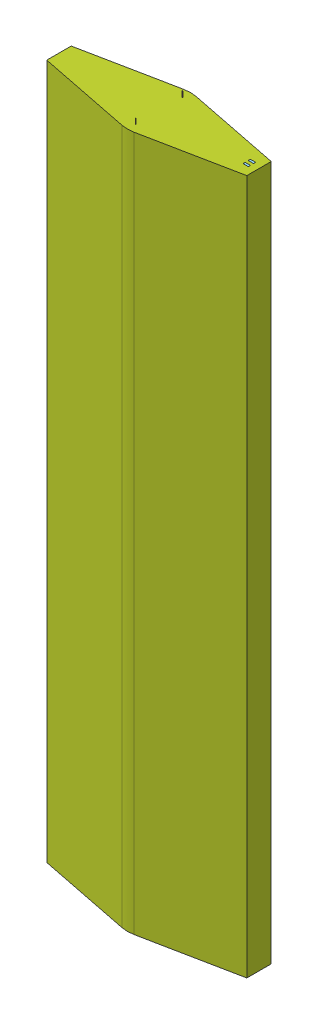
SolidWorks assembly RealString, configuration 默认. Lengths in mm.
Overall size (380 1330.46 350.65).
241 component instances, 7 part files, 3 mates.
Components (placement in the parent):
- RealUnit-1: RealUnit [默认] at origin size (374.87 90.61 350.65)
  - BEGeDet-1: BEGeDet [默认] at (2.9686 -23.0613 80) size (80 40 80)
  - InnerShell-IV-1: InnerShell-IV [默认] at (2.9686 -23.1113 80) x (0.656103 0 0.754671) z (-0.754671 0 0.656103) size (89 50 89)
  - RealOuterShell-IV-Part-3: RealOuterShell-IV-Part [默认] at (2.9686 -24.1113 80) x (-1 0 0) z (0 0 -1) size (357.21 73.56 262.25)
  - RealOuterShell-IV-Part-4: RealOuterShell-IV-Part [默认] at (2.5967 -24.1114 80) x (1 0.000332 0) z (0 0 1) size (357.21 73.56 262.25)
  - Electronics-1: Electronics [默认] at (2.9686 -48.2113 80) x (-1 0 0) z (0 0 -1) size (21.21 85 89.7)
  - ConnectionUnit-1: ConnectionUnit [默认] at (157.8605 -24.8554 155) x (-1 -0.000332 0) z (0 0 -1) size (23 75 26.4)
    - ConnectionRod-IV-1: ConnectionRod-IV [默认] at (-16.742 6.238 75) size (23 75 14)
    - RealSiPMArray-1: RealSiPMArray [默认] at (-11.242 1.238 75) x (-1 0 0) z (0 0 -1) size (3.97 70 26.4)
  - ConnectionUnit-2: ConnectionUnit [默认] at (-152.295 -24.9069 5) size (23 75 26.4)
    - ConnectionRod-IV-1: ConnectionRod-IV [默认] at (-16.742 6.238 75) size (23 75 14)
    - RealSiPMArray-1: RealSiPMArray [默认] at (-11.242 1.238 75) x (-1 0 0) z (0 0 -1) size (3.97 70 26.4)
- RealUnit-2: RealUnit [默认] at (0 65 0) size (374.87 90.61 350.65)
  - BEGeDet-1: BEGeDet [默认] at (2.9686 -23.0613 80) size (80 40 80)
  - InnerShell-IV-1: InnerShell-IV [默认] at (2.9686 -23.1113 80) x (0.656103 0 0.754671) z (-0.754671 0 0.656103) size (89 50 89)
  - RealOuterShell-IV-Part-3: RealOuterShell-IV-Part [默认] at (2.9686 -24.1113 80) x (-1 0 0) z (0 0 -1) size (357.21 73.56 262.25)
  - RealOuterShell-IV-Part-4: RealOuterShell-IV-Part [默认] at (2.5967 -24.1114 80) x (1 0.000332 0) z (0 0 1) size (357.21 73.56 262.25)
  - Electronics-1: Electronics [默认] at (2.9686 -48.2113 80) x (-1 0 0) z (0 0 -1) size (21.21 85 89.7)
  - ConnectionUnit-1: ConnectionUnit [默认] at (157.8605 -24.8554 155) x (-1 -0.000332 0) z (0 0 -1) size (23 75 26.4)
    - ConnectionRod-IV-1: ConnectionRod-IV [默认] at (-16.742 6.238 75) size (23 75 14)
    - RealSiPMArray-1: RealSiPMArray [默认] at (-11.242 1.238 75) x (-1 0 0) z (0 0 -1) size (3.97 70 26.4)
  - ConnectionUnit-2: ConnectionUnit [默认] at (-152.295 -24.9069 5) size (23 75 26.4)
    - ConnectionRod-IV-1: ConnectionRod-IV [默认] at (-16.742 6.238 75) size (23 75 14)
    - RealSiPMArray-1: RealSiPMArray [默认] at (-11.242 1.238 75) x (-1 0 0) z (0 0 -1) size (3.97 70 26.4)
- RealUnit-3: RealUnit [默认] at (0 130 0) size (374.87 90.61 350.65)
  - BEGeDet-1: BEGeDet [默认] at (2.9686 -23.0613 80) size (80 40 80)
  - InnerShell-IV-1: InnerShell-IV [默认] at (2.9686 -23.1113 80) x (0.656103 0 0.754671) z (-0.754671 0 0.656103) size (89 50 89)
  - RealOuterShell-IV-Part-3: RealOuterShell-IV-Part [默认] at (2.9686 -24.1113 80) x (-1 0 0) z (0 0 -1) size (357.21 73.56 262.25)
  - RealOuterShell-IV-Part-4: RealOuterShell-IV-Part [默认] at (2.5967 -24.1114 80) x (1 0.000332 0) z (0 0 1) size (357.21 73.56 262.25)
  - Electronics-1: Electronics [默认] at (2.9686 -48.2113 80) x (-1 0 0) z (0 0 -1) size (21.21 85 89.7)
  - ConnectionUnit-1: ConnectionUnit [默认] at (157.8605 -24.8554 155) x (-1 -0.000332 0) z (0 0 -1) size (23 75 26.4)
    - ConnectionRod-IV-1: ConnectionRod-IV [默认] at (-16.742 6.238 75) size (23 75 14)
    - RealSiPMArray-1: RealSiPMArray [默认] at (-11.242 1.238 75) x (-1 0 0) z (0 0 -1) size (3.97 70 26.4)
  - ConnectionUnit-2: ConnectionUnit [默认] at (-152.295 -24.9069 5) size (23 75 26.4)
    - ConnectionRod-IV-1: ConnectionRod-IV [默认] at (-16.742 6.238 75) size (23 75 14)
    - RealSiPMArray-1: RealSiPMArray [默认] at (-11.242 1.238 75) x (-1 0 0) z (0 0 -1) size (3.97 70 26.4)
- RealUnit-4: RealUnit [默认] at (0 195 0) size (374.87 90.61 350.65)
  - BEGeDet-1: BEGeDet [默认] at (2.9686 -23.0613 80) size (80 40 80)
  - InnerShell-IV-1: InnerShell-IV [默认] at (2.9686 -23.1113 80) x (0.656103 0 0.754671) z (-0.754671 0 0.656103) size (89 50 89)
  - RealOuterShell-IV-Part-3: RealOuterShell-IV-Part [默认] at (2.9686 -24.1113 80) x (-1 0 0) z (0 0 -1) size (357.21 73.56 262.25)
  - RealOuterShell-IV-Part-4: RealOuterShell-IV-Part [默认] at (2.5967 -24.1114 80) x (1 0.000332 0) z (0 0 1) size (357.21 73.56 262.25)
  - Electronics-1: Electronics [默认] at (2.9686 -48.2113 80) x (-1 0 0) z (0 0 -1) size (21.21 85 89.7)
  - ConnectionUnit-1: ConnectionUnit [默认] at (157.8605 -24.8554 155) x (-1 -0.000332 0) z (0 0 -1) size (23 75 26.4)
    - ConnectionRod-IV-1: ConnectionRod-IV [默认] at (-16.742 6.238 75) size (23 75 14)
    - RealSiPMArray-1: RealSiPMArray [默认] at (-11.242 1.238 75) x (-1 0 0) z (0 0 -1) size (3.97 70 26.4)
  - ConnectionUnit-2: ConnectionUnit [默认] at (-152.295 -24.9069 5) size (23 75 26.4)
    - ConnectionRod-IV-1: ConnectionRod-IV [默认] at (-16.742 6.238 75) size (23 75 14)
    - RealSiPMArray-1: RealSiPMArray [默认] at (-11.242 1.238 75) x (-1 0 0) z (0 0 -1) size (3.97 70 26.4)
- RealUnit-5: RealUnit [默认] at (0 260 0) size (374.87 90.61 350.65)
  - BEGeDet-1: BEGeDet [默认] at (2.9686 -23.0613 80) size (80 40 80)
  - InnerShell-IV-1: InnerShell-IV [默认] at (2.9686 -23.1113 80) x (0.656103 0 0.754671) z (-0.754671 0 0.656103) size (89 50 89)
  - RealOuterShell-IV-Part-3: RealOuterShell-IV-Part [默认] at (2.9686 -24.1113 80) x (-1 0 0) z (0 0 -1) size (357.21 73.56 262.25)
  - RealOuterShell-IV-Part-4: RealOuterShell-IV-Part [默认] at (2.5967 -24.1114 80) x (1 0.000332 0) z (0 0 1) size (357.21 73.56 262.25)
  - Electronics-1: Electronics [默认] at (2.9686 -48.2113 80) x (-1 0 0) z (0 0 -1) size (21.21 85 89.7)
  - ConnectionUnit-1: ConnectionUnit [默认] at (157.8605 -24.8554 155) x (-1 -0.000332 0) z (0 0 -1) size (23 75 26.4)
    - ConnectionRod-IV-1: ConnectionRod-IV [默认] at (-16.742 6.238 75) size (23 75 14)
    - RealSiPMArray-1: RealSiPMArray [默认] at (-11.242 1.238 75) x (-1 0 0) z (0 0 -1) size (3.97 70 26.4)
  - ConnectionUnit-2: ConnectionUnit [默认] at (-152.295 -24.9069 5) size (23 75 26.4)
    - ConnectionRod-IV-1: ConnectionRod-IV [默认] at (-16.742 6.238 75) size (23 75 14)
    - RealSiPMArray-1: RealSiPMArray [默认] at (-11.242 1.238 75) x (-1 0 0) z (0 0 -1) size (3.97 70 26.4)
- RealUnit-6: RealUnit [默认] at (0 325 0) size (374.87 90.61 350.65)
  - BEGeDet-1: BEGeDet [默认] at (2.9686 -23.0613 80) size (80 40 80)
  - InnerShell-IV-1: InnerShell-IV [默认] at (2.9686 -23.1113 80) x (0.656103 0 0.754671) z (-0.754671 0 0.656103) size (89 50 89)
  - RealOuterShell-IV-Part-3: RealOuterShell-IV-Part [默认] at (2.9686 -24.1113 80) x (-1 0 0) z (0 0 -1) size (357.21 73.56 262.25)
  - RealOuterShell-IV-Part-4: RealOuterShell-IV-Part [默认] at (2.5967 -24.1114 80) x (1 0.000332 0) z (0 0 1) size (357.21 73.56 262.25)
  - Electronics-1: Electronics [默认] at (2.9686 -48.2113 80) x (-1 0 0) z (0 0 -1) size (21.21 85 89.7)
  - ConnectionUnit-1: ConnectionUnit [默认] at (157.8605 -24.8554 155) x (-1 -0.000332 0) z (0 0 -1) size (23 75 26.4)
    - ConnectionRod-IV-1: ConnectionRod-IV [默认] at (-16.742 6.238 75) size (23 75 14)
    - RealSiPMArray-1: RealSiPMArray [默认] at (-11.242 1.238 75) x (-1 0 0) z (0 0 -1) size (3.97 70 26.4)
  - ConnectionUnit-2: ConnectionUnit [默认] at (-152.295 -24.9069 5) size (23 75 26.4)
    - ConnectionRod-IV-1: ConnectionRod-IV [默认] at (-16.742 6.238 75) size (23 75 14)
    - RealSiPMArray-1: RealSiPMArray [默认] at (-11.242 1.238 75) x (-1 0 0) z (0 0 -1) size (3.97 70 26.4)
- RealUnit-7: RealUnit [默认] at (0 390 0) size (374.87 90.61 350.65)
  - BEGeDet-1: BEGeDet [默认] at (2.9686 -23.0613 80) size (80 40 80)
  - InnerShell-IV-1: InnerShell-IV [默认] at (2.9686 -23.1113 80) x (0.656103 0 0.754671) z (-0.754671 0 0.656103) size (89 50 89)
  - RealOuterShell-IV-Part-3: RealOuterShell-IV-Part [默认] at (2.9686 -24.1113 80) x (-1 0 0) z (0 0 -1) size (357.21 73.56 262.25)
  - RealOuterShell-IV-Part-4: RealOuterShell-IV-Part [默认] at (2.5967 -24.1114 80) x (1 0.000332 0) z (0 0 1) size (357.21 73.56 262.25)
  - Electronics-1: Electronics [默认] at (2.9686 -48.2113 80) x (-1 0 0) z (0 0 -1) size (21.21 85 89.7)
  - ConnectionUnit-1: ConnectionUnit [默认] at (157.8605 -24.8554 155) x (-1 -0.000332 0) z (0 0 -1) size (23 75 26.4)
    - ConnectionRod-IV-1: ConnectionRod-IV [默认] at (-16.742 6.238 75) size (23 75 14)
    - RealSiPMArray-1: RealSiPMArray [默认] at (-11.242 1.238 75) x (-1 0 0) z (0 0 -1) size (3.97 70 26.4)
  - ConnectionUnit-2: ConnectionUnit [默认] at (-152.295 -24.9069 5) size (23 75 26.4)
    - ConnectionRod-IV-1: ConnectionRod-IV [默认] at (-16.742 6.238 75) size (23 75 14)
    - RealSiPMArray-1: RealSiPMArray [默认] at (-11.242 1.238 75) x (-1 0 0) z (0 0 -1) size (3.97 70 26.4)
- RealUnit-8: RealUnit [默认] at (0 455 0) size (374.87 90.61 350.65)
  - BEGeDet-1: BEGeDet [默认] at (2.9686 -23.0613 80) size (80 40 80)
  - InnerShell-IV-1: InnerShell-IV [默认] at (2.9686 -23.1113 80) x (0.656103 0 0.754671) z (-0.754671 0 0.656103) size (89 50 89)
  - RealOuterShell-IV-Part-3: RealOuterShell-IV-Part [默认] at (2.9686 -24.1113 80) x (-1 0 0) z (0 0 -1) size (357.21 73.56 262.25)
  - RealOuterShell-IV-Part-4: RealOuterShell-IV-Part [默认] at (2.5967 -24.1114 80) x (1 0.000332 0) z (0 0 1) size (357.21 73.56 262.25)
  - Electronics-1: Electronics [默认] at (2.9686 -48.2113 80) x (-1 0 0) z (0 0 -1) size (21.21 85 89.7)
  - ConnectionUnit-1: ConnectionUnit [默认] at (157.8605 -24.8554 155) x (-1 -0.000332 0) z (0 0 -1) size (23 75 26.4)
    - ConnectionRod-IV-1: ConnectionRod-IV [默认] at (-16.742 6.238 75) size (23 75 14)
    - RealSiPMArray-1: RealSiPMArray [默认] at (-11.242 1.238 75) x (-1 0 0) z (0 0 -1) size (3.97 70 26.4)
  - ConnectionUnit-2: ConnectionUnit [默认] at (-152.295 -24.9069 5) size (23 75 26.4)
    - ConnectionRod-IV-1: ConnectionRod-IV [默认] at (-16.742 6.238 75) size (23 75 14)
    - RealSiPMArray-1: RealSiPMArray [默认] at (-11.242 1.238 75) x (-1 0 0) z (0 0 -1) size (3.97 70 26.4)
- RealUnit-9: RealUnit [默认] at (0 520 0) size (374.87 90.61 350.65)
  - BEGeDet-1: BEGeDet [默认] at (2.9686 -23.0613 80) size (80 40 80)
  - InnerShell-IV-1: InnerShell-IV [默认] at (2.9686 -23.1113 80) x (0.656103 0 0.754671) z (-0.754671 0 0.656103) size (89 50 89)
  - RealOuterShell-IV-Part-3: RealOuterShell-IV-Part [默认] at (2.9686 -24.1113 80) x (-1 0 0) z (0 0 -1) size (357.21 73.56 262.25)
  - RealOuterShell-IV-Part-4: RealOuterShell-IV-Part [默认] at (2.5967 -24.1114 80) x (1 0.000332 0) z (0 0 1) size (357.21 73.56 262.25)
  - Electronics-1: Electronics [默认] at (2.9686 -48.2113 80) x (-1 0 0) z (0 0 -1) size (21.21 85 89.7)
  - ConnectionUnit-1: ConnectionUnit [默认] at (157.8605 -24.8554 155) x (-1 -0.000332 0) z (0 0 -1) size (23 75 26.4)
    - ConnectionRod-IV-1: ConnectionRod-IV [默认] at (-16.742 6.238 75) size (23 75 14)
    - RealSiPMArray-1: RealSiPMArray [默认] at (-11.242 1.238 75) x (-1 0 0) z (0 0 -1) size (3.97 70 26.4)
  - ConnectionUnit-2: ConnectionUnit [默认] at (-152.295 -24.9069 5) size (23 75 26.4)
    - ConnectionRod-IV-1: ConnectionRod-IV [默认] at (-16.742 6.238 75) size (23 75 14)
    - RealSiPMArray-1: RealSiPMArray [默认] at (-11.242 1.238 75) x (-1 0 0) z (0 0 -1) size (3.97 70 26.4)
- RealUnit-10: RealUnit [默认] at (0 585 0) size (374.87 90.61 350.65)
  - BEGeDet-1: BEGeDet [默认] at (2.9686 -23.0613 80) size (80 40 80)
  - InnerShell-IV-1: InnerShell-IV [默认] at (2.9686 -23.1113 80) x (0.656103 0 0.754671) z (-0.754671 0 0.656103) size (89 50 89)
  - RealOuterShell-IV-Part-3: RealOuterShell-IV-Part [默认] at (2.9686 -24.1113 80) x (-1 0 0) z (0 0 -1) size (357.21 73.56 262.25)
  - RealOuterShell-IV-Part-4: RealOuterShell-IV-Part [默认] at (2.5967 -24.1114 80) x (1 0.000332 0) z (0 0 1) size (357.21 73.56 262.25)
  - Electronics-1: Electronics [默认] at (2.9686 -48.2113 80) x (-1 0 0) z (0 0 -1) size (21.21 85 89.7)
  - ConnectionUnit-1: ConnectionUnit [默认] at (157.8605 -24.8554 155) x (-1 -0.000332 0) z (0 0 -1) size (23 75 26.4)
    - ConnectionRod-IV-1: ConnectionRod-IV [默认] at (-16.742 6.238 75) size (23 75 14)
    - RealSiPMArray-1: RealSiPMArray [默认] at (-11.242 1.238 75) x (-1 0 0) z (0 0 -1) size (3.97 70 26.4)
  - ConnectionUnit-2: ConnectionUnit [默认] at (-152.295 -24.9069 5) size (23 75 26.4)
    - ConnectionRod-IV-1: ConnectionRod-IV [默认] at (-16.742 6.238 75) size (23 75 14)
    - RealSiPMArray-1: RealSiPMArray [默认] at (-11.242 1.238 75) x (-1 0 0) z (0 0 -1) size (3.97 70 26.4)
- RealUnit-11: RealUnit [默认] at (0 650 0) size (374.87 90.61 350.65)
  - BEGeDet-1: BEGeDet [默认] at (2.9686 -23.0613 80) size (80 40 80)
  - InnerShell-IV-1: InnerShell-IV [默认] at (2.9686 -23.1113 80) x (0.656103 0 0.754671) z (-0.754671 0 0.656103) size (89 50 89)
  - RealOuterShell-IV-Part-3: RealOuterShell-IV-Part [默认] at (2.9686 -24.1113 80) x (-1 0 0) z (0 0 -1) size (357.21 73.56 262.25)
  - RealOuterShell-IV-Part-4: RealOuterShell-IV-Part [默认] at (2.5967 -24.1114 80) x (1 0.000332 0) z (0 0 1) size (357.21 73.56 262.25)
  - Electronics-1: Electronics [默认] at (2.9686 -48.2113 80) x (-1 0 0) z (0 0 -1) size (21.21 85 89.7)
  - ConnectionUnit-1: ConnectionUnit [默认] at (157.8605 -24.8554 155) x (-1 -0.000332 0) z (0 0 -1) size (23 75 26.4)
    - ConnectionRod-IV-1: ConnectionRod-IV [默认] at (-16.742 6.238 75) size (23 75 14)
    - RealSiPMArray-1: RealSiPMArray [默认] at (-11.242 1.238 75) x (-1 0 0) z (0 0 -1) size (3.97 70 26.4)
  - ConnectionUnit-2: ConnectionUnit [默认] at (-152.295 -24.9069 5) size (23 75 26.4)
    - ConnectionRod-IV-1: ConnectionRod-IV [默认] at (-16.742 6.238 75) size (23 75 14)
    - RealSiPMArray-1: RealSiPMArray [默认] at (-11.242 1.238 75) x (-1 0 0) z (0 0 -1) size (3.97 70 26.4)
- RealUnit-12: RealUnit [默认] at (0 715 0) size (374.87 90.61 350.65)
  - BEGeDet-1: BEGeDet [默认] at (2.9686 -23.0613 80) size (80 40 80)
  - InnerShell-IV-1: InnerShell-IV [默认] at (2.9686 -23.1113 80) x (0.656103 0 0.754671) z (-0.754671 0 0.656103) size (89 50 89)
  - RealOuterShell-IV-Part-3: RealOuterShell-IV-Part [默认] at (2.9686 -24.1113 80) x (-1 0 0) z (0 0 -1) size (357.21 73.56 262.25)
  - RealOuterShell-IV-Part-4: RealOuterShell-IV-Part [默认] at (2.5967 -24.1114 80) x (1 0.000332 0) z (0 0 1) size (357.21 73.56 262.25)
  - Electronics-1: Electronics [默认] at (2.9686 -48.2113 80) x (-1 0 0) z (0 0 -1) size (21.21 85 89.7)
  - ConnectionUnit-1: ConnectionUnit [默认] at (157.8605 -24.8554 155) x (-1 -0.000332 0) z (0 0 -1) size (23 75 26.4)
    - ConnectionRod-IV-1: ConnectionRod-IV [默认] at (-16.742 6.238 75) size (23 75 14)
    - RealSiPMArray-1: RealSiPMArray [默认] at (-11.242 1.238 75) x (-1 0 0) z (0 0 -1) size (3.97 70 26.4)
  - ConnectionUnit-2: ConnectionUnit [默认] at (-152.295 -24.9069 5) size (23 75 26.4)
    - ConnectionRod-IV-1: ConnectionRod-IV [默认] at (-16.742 6.238 75) size (23 75 14)
    - RealSiPMArray-1: RealSiPMArray [默认] at (-11.242 1.238 75) x (-1 0 0) z (0 0 -1) size (3.97 70 26.4)
- RealUnit-13: RealUnit [默认] at (0 780 0) size (374.87 90.61 350.65)
  - BEGeDet-1: BEGeDet [默认] at (2.9686 -23.0613 80) size (80 40 80)
  - InnerShell-IV-1: InnerShell-IV [默认] at (2.9686 -23.1113 80) x (0.656103 0 0.754671) z (-0.754671 0 0.656103) size (89 50 89)
  - RealOuterShell-IV-Part-3: RealOuterShell-IV-Part [默认] at (2.9686 -24.1113 80) x (-1 0 0) z (0 0 -1) size (357.21 73.56 262.25)
  - RealOuterShell-IV-Part-4: RealOuterShell-IV-Part [默认] at (2.5967 -24.1114 80) x (1 0.000332 0) z (0 0 1) size (357.21 73.56 262.25)
  - Electronics-1: Electronics [默认] at (2.9686 -48.2113 80) x (-1 0 0) z (0 0 -1) size (21.21 85 89.7)
  - ConnectionUnit-1: ConnectionUnit [默认] at (157.8605 -24.8554 155) x (-1 -0.000332 0) z (0 0 -1) size (23 75 26.4)
    - ConnectionRod-IV-1: ConnectionRod-IV [默认] at (-16.742 6.238 75) size (23 75 14)
    - RealSiPMArray-1: RealSiPMArray [默认] at (-11.242 1.238 75) x (-1 0 0) z (0 0 -1) size (3.97 70 26.4)
  - ConnectionUnit-2: ConnectionUnit [默认] at (-152.295 -24.9069 5) size (23 75 26.4)
    - ConnectionRod-IV-1: ConnectionRod-IV [默认] at (-16.742 6.238 75) size (23 75 14)
    - RealSiPMArray-1: RealSiPMArray [默认] at (-11.242 1.238 75) x (-1 0 0) z (0 0 -1) size (3.97 70 26.4)
- RealUnit-14: RealUnit [默认] at (0 845 0) size (374.87 90.61 350.65)
  - BEGeDet-1: BEGeDet [默认] at (2.9686 -23.0613 80) size (80 40 80)
  - InnerShell-IV-1: InnerShell-IV [默认] at (2.9686 -23.1113 80) x (0.656103 0 0.754671) z (-0.754671 0 0.656103) size (89 50 89)
  - RealOuterShell-IV-Part-3: RealOuterShell-IV-Part [默认] at (2.9686 -24.1113 80) x (-1 0 0) z (0 0 -1) size (357.21 73.56 262.25)
  - RealOuterShell-IV-Part-4: RealOuterShell-IV-Part [默认] at (2.5967 -24.1114 80) x (1 0.000332 0) z (0 0 1) size (357.21 73.56 262.25)
  - Electronics-1: Electronics [默认] at (2.9686 -48.2113 80) x (-1 0 0) z (0 0 -1) size (21.21 85 89.7)
  - ConnectionUnit-1: ConnectionUnit [默认] at (157.8605 -24.8554 155) x (-1 -0.000332 0) z (0 0 -1) size (23 75 26.4)
    - ConnectionRod-IV-1: ConnectionRod-IV [默认] at (-16.742 6.238 75) size (23 75 14)
    - RealSiPMArray-1: RealSiPMArray [默认] at (-11.242 1.238 75) x (-1 0 0) z (0 0 -1) size (3.97 70 26.4)
  - ConnectionUnit-2: ConnectionUnit [默认] at (-152.295 -24.9069 5) size (23 75 26.4)
    - ConnectionRod-IV-1: ConnectionRod-IV [默认] at (-16.742 6.238 75) size (23 75 14)
    - RealSiPMArray-1: RealSiPMArray [默认] at (-11.242 1.238 75) x (-1 0 0) z (0 0 -1) size (3.97 70 26.4)
- RealUnit-15: RealUnit [默认] at (0 910 0) size (374.87 90.61 350.65)
  - BEGeDet-1: BEGeDet [默认] at (2.9686 -23.0613 80) size (80 40 80)
  - InnerShell-IV-1: InnerShell-IV [默认] at (2.9686 -23.1113 80) x (0.656103 0 0.754671) z (-0.754671 0 0.656103) size (89 50 89)
  - RealOuterShell-IV-Part-3: RealOuterShell-IV-Part [默认] at (2.9686 -24.1113 80) x (-1 0 0) z (0 0 -1) size (357.21 73.56 262.25)
  - RealOuterShell-IV-Part-4: RealOuterShell-IV-Part [默认] at (2.5967 -24.1114 80) x (1 0.000332 0) z (0 0 1) size (357.21 73.56 262.25)
  - Electronics-1: Electronics [默认] at (2.9686 -48.2113 80) x (-1 0 0) z (0 0 -1) size (21.21 85 89.7)
  - ConnectionUnit-1: ConnectionUnit [默认] at (157.8605 -24.8554 155) x (-1 -0.000332 0) z (0 0 -1) size (23 75 26.4)
    - ConnectionRod-IV-1: ConnectionRod-IV [默认] at (-16.742 6.238 75) size (23 75 14)
    - RealSiPMArray-1: RealSiPMArray [默认] at (-11.242 1.238 75) x (-1 0 0) z (0 0 -1) size (3.97 70 26.4)
  - ConnectionUnit-2: ConnectionUnit [默认] at (-152.295 -24.9069 5) size (23 75 26.4)
    - ConnectionRod-IV-1: ConnectionRod-IV [默认] at (-16.742 6.238 75) size (23 75 14)
    - RealSiPMArray-1: RealSiPMArray [默认] at (-11.242 1.238 75) x (-1 0 0) z (0 0 -1) size (3.97 70 26.4)
- RealUnit-16: RealUnit [默认] at (0 975 0) size (374.87 90.61 350.65)
  - BEGeDet-1: BEGeDet [默认] at (2.9686 -23.0613 80) size (80 40 80)
  - InnerShell-IV-1: InnerShell-IV [默认] at (2.9686 -23.1113 80) x (0.656103 0 0.754671) z (-0.754671 0 0.656103) size (89 50 89)
  - RealOuterShell-IV-Part-3: RealOuterShell-IV-Part [默认] at (2.9686 -24.1113 80) x (-1 0 0) z (0 0 -1) size (357.21 73.56 262.25)
  - RealOuterShell-IV-Part-4: RealOuterShell-IV-Part [默认] at (2.5967 -24.1114 80) x (1 0.000332 0) z (0 0 1) size (357.21 73.56 262.25)
  - Electronics-1: Electronics [默认] at (2.9686 -48.2113 80) x (-1 0 0) z (0 0 -1) size (21.21 85 89.7)
  - ConnectionUnit-1: ConnectionUnit [默认] at (157.8605 -24.8554 155) x (-1 -0.000332 0) z (0 0 -1) size (23 75 26.4)
    - ConnectionRod-IV-1: ConnectionRod-IV [默认] at (-16.742 6.238 75) size (23 75 14)
    - RealSiPMArray-1: RealSiPMArray [默认] at (-11.242 1.238 75) x (-1 0 0) z (0 0 -1) size (3.97 70 26.4)
  - ConnectionUnit-2: ConnectionUnit [默认] at (-152.295 -24.9069 5) size (23 75 26.4)
    - ConnectionRod-IV-1: ConnectionRod-IV [默认] at (-16.742 6.238 75) size (23 75 14)
    - RealSiPMArray-1: RealSiPMArray [默认] at (-11.242 1.238 75) x (-1 0 0) z (0 0 -1) size (3.97 70 26.4)
- RealUnit-17: RealUnit [默认] at (0 1040 0) size (374.87 90.61 350.65)
  - BEGeDet-1: BEGeDet [默认] at (2.9686 -23.0613 80) size (80 40 80)
  - InnerShell-IV-1: InnerShell-IV [默认] at (2.9686 -23.1113 80) x (0.656103 0 0.754671) z (-0.754671 0 0.656103) size (89 50 89)
  - RealOuterShell-IV-Part-3: RealOuterShell-IV-Part [默认] at (2.9686 -24.1113 80) x (-1 0 0) z (0 0 -1) size (357.21 73.56 262.25)
  - RealOuterShell-IV-Part-4: RealOuterShell-IV-Part [默认] at (2.5967 -24.1114 80) x (1 0.000332 0) z (0 0 1) size (357.21 73.56 262.25)
  - Electronics-1: Electronics [默认] at (2.9686 -48.2113 80) x (-1 0 0) z (0 0 -1) size (21.21 85 89.7)
  - ConnectionUnit-1: ConnectionUnit [默认] at (157.8605 -24.8554 155) x (-1 -0.000332 0) z (0 0 -1) size (23 75 26.4)
    - ConnectionRod-IV-1: ConnectionRod-IV [默认] at (-16.742 6.238 75) size (23 75 14)
    - RealSiPMArray-1: RealSiPMArray [默认] at (-11.242 1.238 75) x (-1 0 0) z (0 0 -1) size (3.97 70 26.4)
  - ConnectionUnit-2: ConnectionUnit [默认] at (-152.295 -24.9069 5) size (23 75 26.4)
    - ConnectionRod-IV-1: ConnectionRod-IV [默认] at (-16.742 6.238 75) size (23 75 14)
    - RealSiPMArray-1: RealSiPMArray [默认] at (-11.242 1.238 75) x (-1 0 0) z (0 0 -1) size (3.97 70 26.4)
- RealUnit-18: RealUnit [默认] at (0 1105 0) size (374.87 90.61 350.65)
  - BEGeDet-1: BEGeDet [默认] at (2.9686 -23.0613 80) size (80 40 80)
  - InnerShell-IV-1: InnerShell-IV [默认] at (2.9686 -23.1113 80) x (0.656103 0 0.754671) z (-0.754671 0 0.656103) size (89 50 89)
  - RealOuterShell-IV-Part-3: RealOuterShell-IV-Part [默认] at (2.9686 -24.1113 80) x (-1 0 0) z (0 0 -1) size (357.21 73.56 262.25)
  - RealOuterShell-IV-Part-4: RealOuterShell-IV-Part [默认] at (2.5967 -24.1114 80) x (1 0.000332 0) z (0 0 1) size (357.21 73.56 262.25)
  - Electronics-1: Electronics [默认] at (2.9686 -48.2113 80) x (-1 0 0) z (0 0 -1) size (21.21 85 89.7)
  - ConnectionUnit-1: ConnectionUnit [默认] at (157.8605 -24.8554 155) x (-1 -0.000332 0) z (0 0 -1) size (23 75 26.4)
    - ConnectionRod-IV-1: ConnectionRod-IV [默认] at (-16.742 6.238 75) size (23 75 14)
    - RealSiPMArray-1: RealSiPMArray [默认] at (-11.242 1.238 75) x (-1 0 0) z (0 0 -1) size (3.97 70 26.4)
  - ConnectionUnit-2: ConnectionUnit [默认] at (-152.295 -24.9069 5) size (23 75 26.4)
    - ConnectionRod-IV-1: ConnectionRod-IV [默认] at (-16.742 6.238 75) size (23 75 14)
    - RealSiPMArray-1: RealSiPMArray [默认] at (-11.242 1.238 75) x (-1 0 0) z (0 0 -1) size (3.97 70 26.4)
- RealUnit-19: RealUnit [默认] at (0 1170 0) size (374.87 90.61 350.65)
  - BEGeDet-1: BEGeDet [默认] at (2.9686 -23.0613 80) size (80 40 80)
  - InnerShell-IV-1: InnerShell-IV [默认] at (2.9686 -23.1113 80) x (0.656103 0 0.754671) z (-0.754671 0 0.656103) size (89 50 89)
  - RealOuterShell-IV-Part-3: RealOuterShell-IV-Part [默认] at (2.9686 -24.1113 80) x (-1 0 0) z (0 0 -1) size (357.21 73.56 262.25)
  - RealOuterShell-IV-Part-4: RealOuterShell-IV-Part [默认] at (2.5967 -24.1114 80) x (1 0.000332 0) z (0 0 1) size (357.21 73.56 262.25)
  - Electronics-1: Electronics [默认] at (2.9686 -48.2113 80) x (-1 0 0) z (0 0 -1) size (21.21 85 89.7)
  - ConnectionUnit-1: ConnectionUnit [默认] at (157.8605 -24.8554 155) x (-1 -0.000332 0) z (0 0 -1) size (23 75 26.4)
    - ConnectionRod-IV-1: ConnectionRod-IV [默认] at (-16.742 6.238 75) size (23 75 14)
    - RealSiPMArray-1: RealSiPMArray [默认] at (-11.242 1.238 75) x (-1 0 0) z (0 0 -1) size (3.97 70 26.4)
  - ConnectionUnit-2: ConnectionUnit [默认] at (-152.295 -24.9069 5) size (23 75 26.4)
    - ConnectionRod-IV-1: ConnectionRod-IV [默认] at (-16.742 6.238 75) size (23 75 14)
    - RealSiPMArray-1: RealSiPMArray [默认] at (-11.242 1.238 75) x (-1 0 0) z (0 0 -1) size (3.97 70 26.4)
- RealUnit-20: RealUnit [默认] at (0 1235 0) size (374.87 90.61 350.65)
  - BEGeDet-1: BEGeDet [默认] at (2.9686 -23.0613 80) size (80 40 80)
  - InnerShell-IV-1: InnerShell-IV [默认] at (2.9686 -23.1113 80) x (0.656103 0 0.754671) z (-0.754671 0 0.656103) size (89 50 89)
  - RealOuterShell-IV-Part-3: RealOuterShell-IV-Part [默认] at (2.9686 -24.1113 80) x (-1 0 0) z (0 0 -1) size (357.21 73.56 262.25)
  - RealOuterShell-IV-Part-4: RealOuterShell-IV-Part [默认] at (2.5967 -24.1114 80) x (1 0.000332 0) z (0 0 1) size (357.21 73.56 262.25)
  - Electronics-1: Electronics [默认] at (2.9686 -48.2113 80) x (-1 0 0) z (0 0 -1) size (21.21 85 89.7)
  - ConnectionUnit-1: ConnectionUnit [默认] at (157.8605 -24.8554 155) x (-1 -0.000332 0) z (0 0 -1) size (23 75 26.4)
    - ConnectionRod-IV-1: ConnectionRod-IV [默认] at (-16.742 6.238 75) size (23 75 14)
    - RealSiPMArray-1: RealSiPMArray [默认] at (-11.242 1.238 75) x (-1 0 0) z (0 0 -1) size (3.97 70 26.4)
  - ConnectionUnit-2: ConnectionUnit [默认] at (-152.295 -24.9069 5) size (23 75 26.4)
    - ConnectionRod-IV-1: ConnectionRod-IV [默认] at (-16.742 6.238 75) size (23 75 14)
    - RealSiPMArray-1: RealSiPMArray [默认] at (-11.242 1.238 75) x (-1 0 0) z (0 0 -1) size (3.97 70 26.4)
- StringBox-IV-1: StringBox-IV [默认] at (2.9686 588.8311 80) size (380 1320 120)
Mates (geometry in assembly coordinates):
- 重合1: coincident anti-aligned: plane of RealUnit-1/ConnectionUnit-2/ConnectionRod-IV-1 through (-164.037 -61.1689 83) normal (0 -1 0); plane of StringBox-IV-1 through (2.9686 -61.1689 80) normal (0 1 0)
- 同心3: concentric aligned: circle of RealUnit-20/BEGeDet-1; circle of StringBox-IV-1
- 平行6: parallel anti-aligned: plane of RealUnit-20/RealOuterShell-IV-Part-3 through (252.9686 1180.8887 80) normal (0.196 0 -0.980604); plane of StringBox-IV-1 through (182.9686 1238.8311 64.9888) normal (-0.196 0 0.980604)
